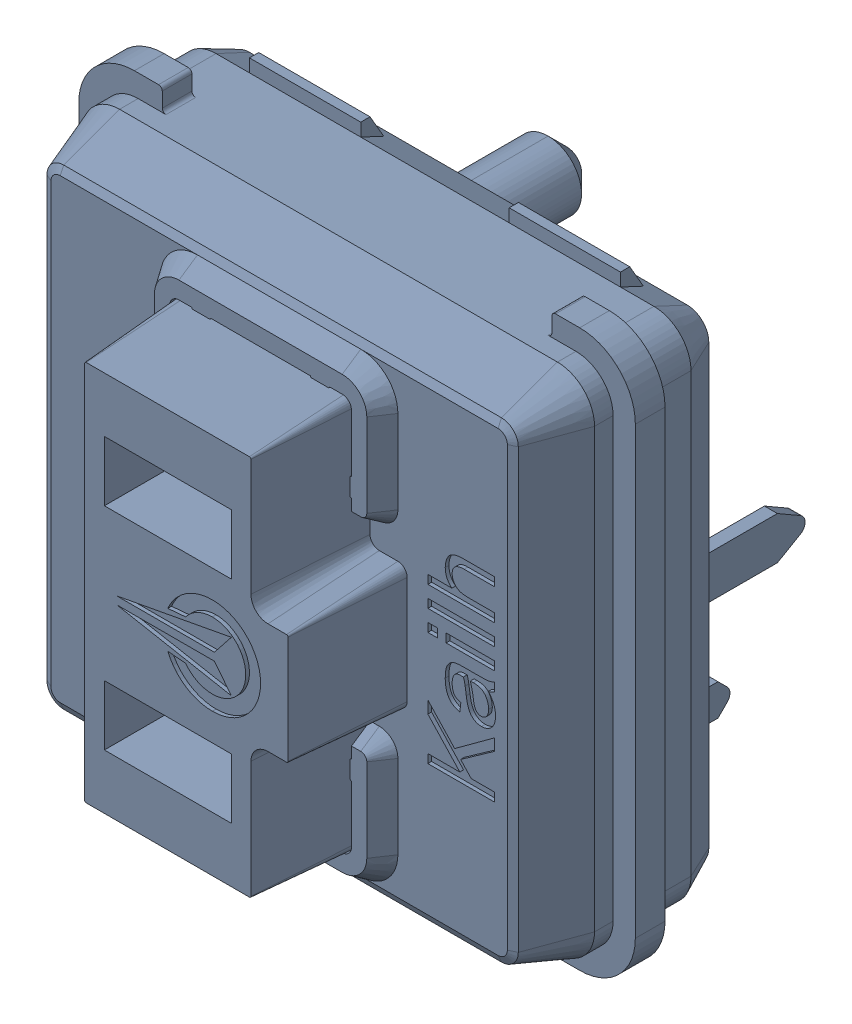
SolidWorks assembly SW6_1.step, configuration Default. Lengths in mm.
Overall size (15 15 11.1).
2 component instances, 2 part files, 0 mates.
Components (placement in the parent):
- Kailh LP Choc Burnt Orange_1.step-11: Kailh LP Choc Burnt Orange_1.step [Default] at (465.9499 283.4846 2.7) x (1 0 0) z (0 -1 0) size (15 11.1 15)
- WS2812-2020_1.step-11: WS2812-2020_1.step [Default] at (461.3087 283.5912 0.3) x (0 1 0) z (1 0 0) size (2.2 0.86 2)
